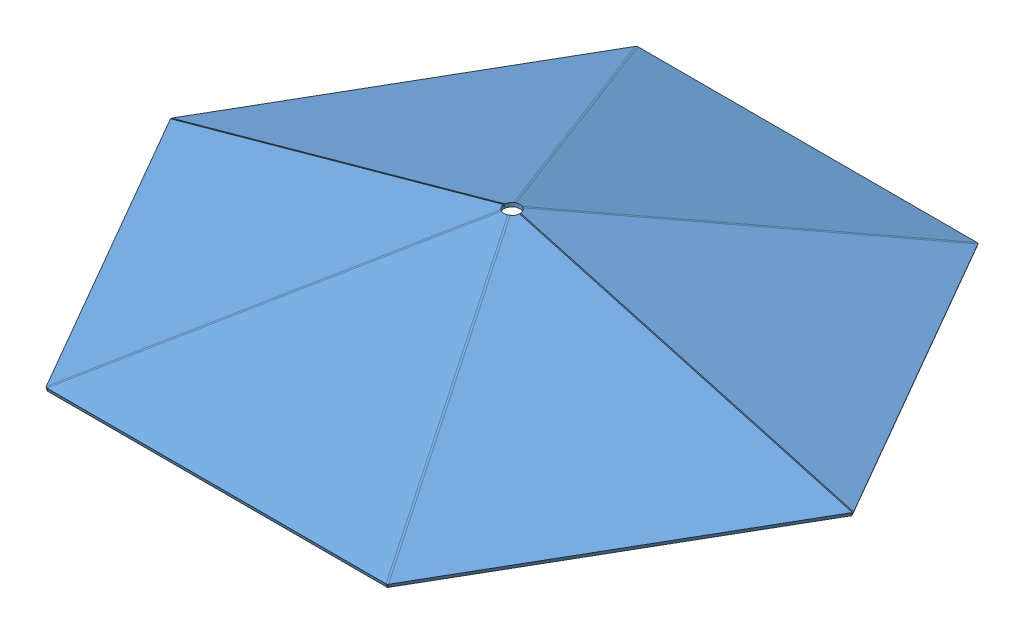
SolidWorks assembly Ensamblaje2, configuration Predeterminado. Lengths in mm.
Overall size (278.1 39.24 241.34).
2 component instances, 1 part files, 3 mates.
Components (placement in the parent):
- hood-1: hood [Predeterminado] at origin size (278.1 39.63 120.67)
- hood-2: hood [Predeterminado] x (-1 0 0) z (0 0 -1) size (278.1 39.63 120.67)
Mates (geometry in assembly coordinates):
- Coincidente2: coincident anti-aligned: plane of hood-2 through (0 0 0) normal (0 0 -1); plane of assembly through (0 0 0) normal (0 0 1)
- Coincidente3: coincident anti-aligned: plane of hood-2 through (0 0 0) normal (-1 0 0); plane of assembly through (0 0 0) normal (1 0 0)
- Coincidente4: coincident aligned: plane of hood-2; plane of assembly through (0 0 0) normal (0 1 0)
